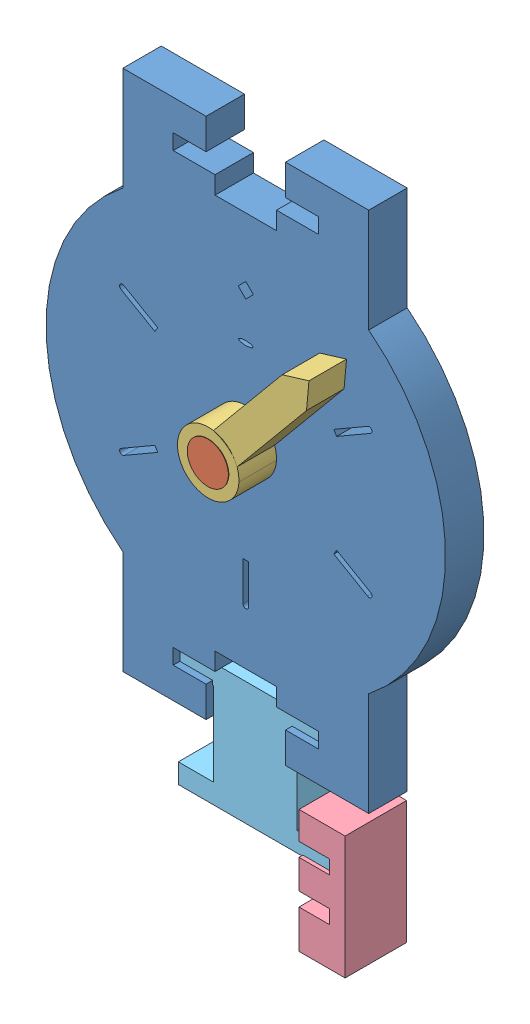
SolidWorks assembly Assem2, configuration Default. Lengths in mm.
Overall size (33.02 56.16 8.77).
5 component instances, 5 part files, 2 mates.
Components (placement in the parent):
- Sketched Watch Face-1: Sketched Watch Face [Default] at (14.1347 23.1216 32.204) size (33.02 43.18 3.17)
- pin-1: pin [Default] at (14.0559 23.0678 32.1667) x (0.563835 -0.825888 0) z (0 0 1) size (3.4 3.4 6.35)
- hour hand-1: hour hand [Default] at (14.1347 23.1216 35.3074) x (0.768991 -0.639259 0) z (0 0 1) size (5.08 15.56 3.17)
- Watch link side-1: Watch link side [Default] at (20.2044 -5.8566 30.0681) size (3.81 10.16 5.08)
- watch middle link-1: watch middle link [Default] at (14.3579 0.2696 29.7487) size (12.7 10.16 5.08)
Mates (geometry in assembly coordinates):
- Concentric2: concentric aligned: circle of Sketched Watch Face-1; circle of hour hand-1
- Concentric3: concentric aligned: circle of pin-1; circle of hour hand-1
